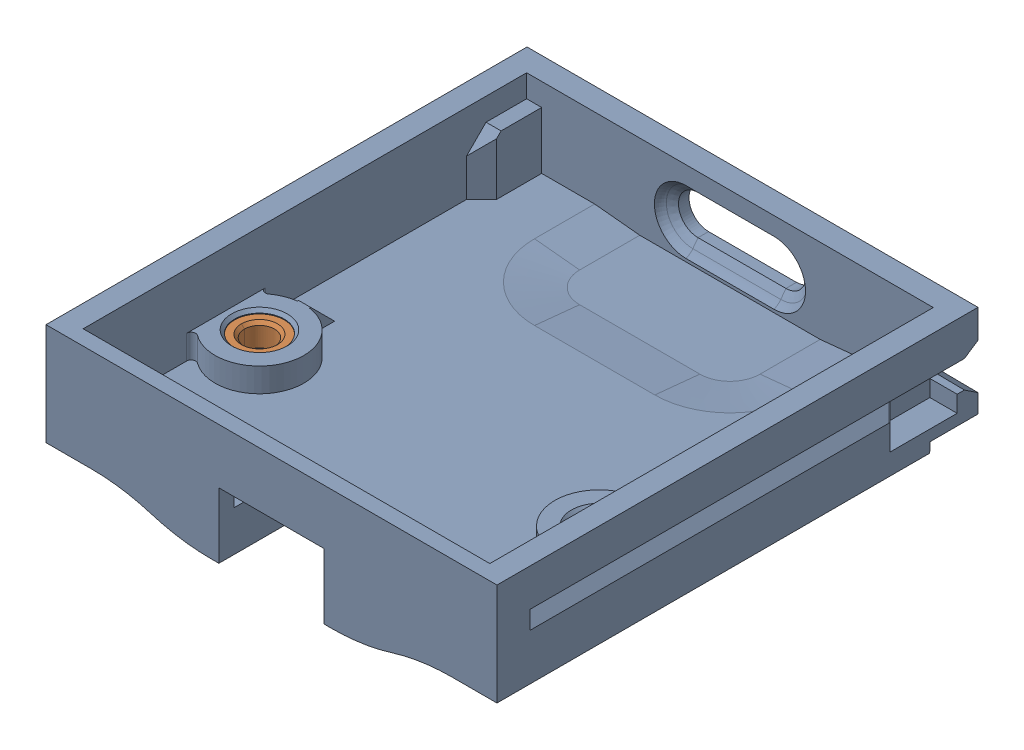
SolidWorks assembly FW_EXP_1USBC_FRAME_CLIP_BC_ASSY_ASM, configuration Default. Lengths in mm.
Overall size (30 8 32).
3 component instances, 2 part files, 0 mates.
Components (placement in the parent):
- cardcase-1: cardcase [Default] at origin size (30 8 32)
- NUT_M2X1-6L_2-1: NUT_M2X1-6L_2 [Default] at (-11.3 2.85 -10.5) size (3.6 1.5 3.6)
- NUT_M2X1-6L_2-2: NUT_M2X1-6L_2 [Default] at (11.3 2.85 -10.5) size (3.6 1.5 3.6)
